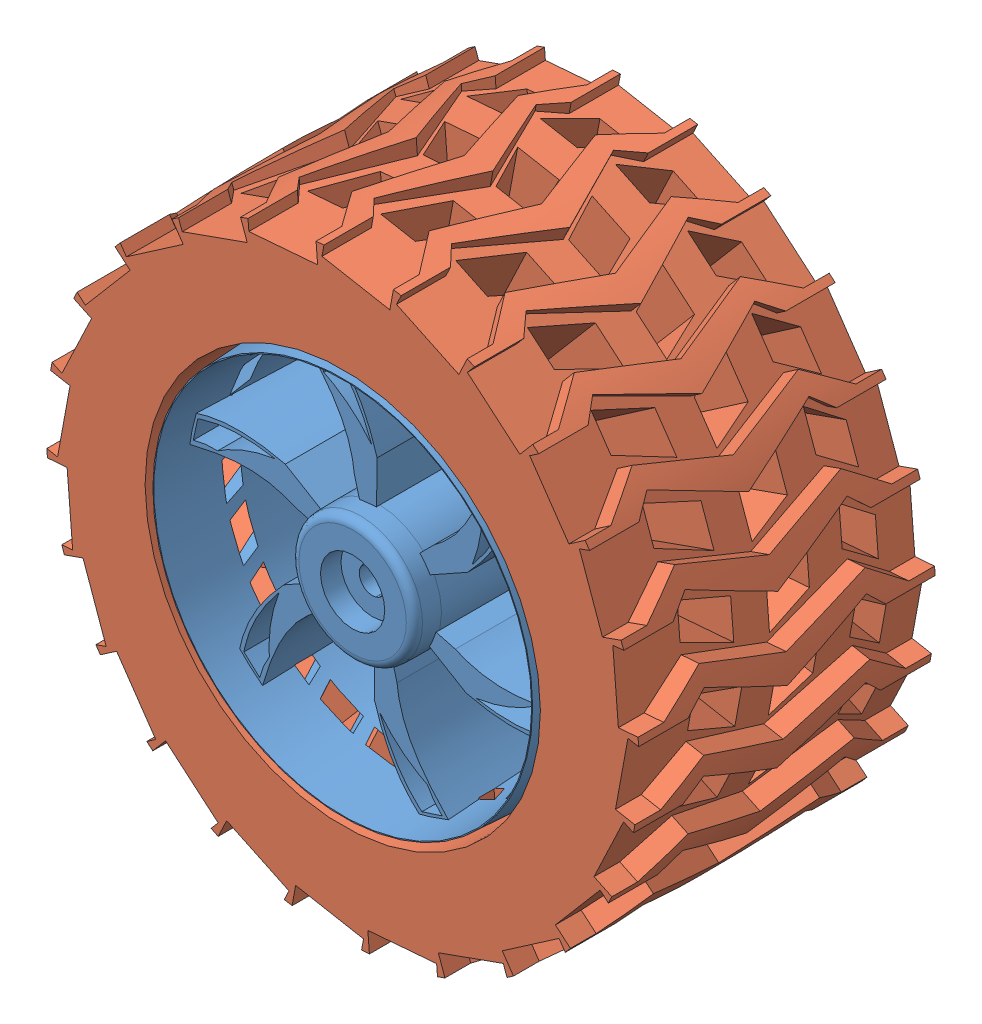
SolidWorks assembly Wheel assembly with motor, configuration Default. Lengths in mm.
Overall size (125.19 125.19 45).
2 component instances, 2 part files, 4 mates.
Components (placement in the parent):
- wheel-1: wheel [Default] at (25.5285 33.2647 43.0752) size (60 60 45)
- tyre-1: tyre [Default] at (25.5285 33.2647 65.5752) x (0 0 -1) z (0.823199 0.567753 0) size (45 90 90)
Mates (geometry in assembly coordinates):
- Coincident1: coincident aligned: circle of wheel-1; cylinder of tyre-1 through (25.5285 33.2647 20.5752) axis (0 0 1) radius 30
- Width1: width anti-aligned: plane of tyre-1 through (25.5285 33.2647 65.5752) normal (0 0 1); plane of wheel-1 through (25.5285 33.2647 20.5752) normal (0 0 -1); plane of tyre-1 through (25.5285 33.2647 20.5752) normal (0 0 -1); plane of wheel-1 through (25.5285 33.2647 65.5752) normal (0 0 1)
- Concentric2: concentric anti-aligned: cone of wheel-1 through (25.5285 33.2647 60.0752) axis (0 0 -1); cylinder of motor12v-2 through (25.5285 33.2647 58.0752) axis (0 0 1) radius 4.725
- Coincident2: coincident anti-aligned: plane of wheel-1 through (25.5285 33.2647 64.0752) normal (0 0 1); plane of motor12v-2 through (25.5285 33.2647 64.0752) normal (0 0 -1)
